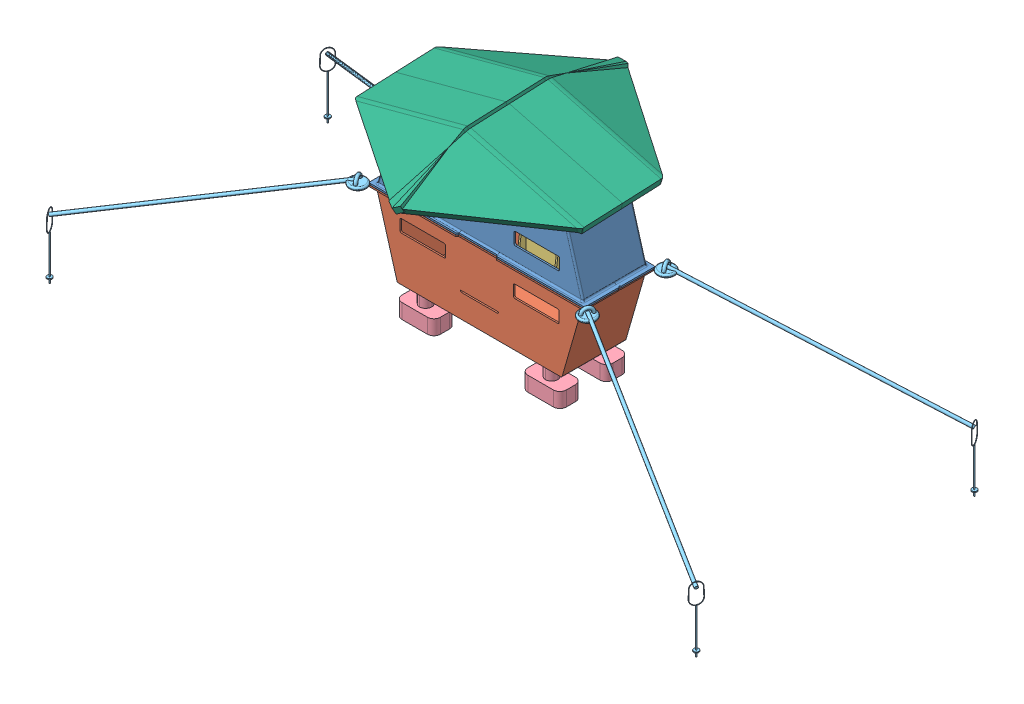
SolidWorks assembly one house, configuration Default. Lengths in mm.
Overall size (1032.67 408.62 463.62).
12 component instances, 6 part files, 7 mates.
Components (placement in the parent):
- cover up-1: cover up [Default] at (-101.023 235.1735 197.7428) size (378.85 222.42 111.15)
- cover down-1: cover down [Default] at (-101.6635 230.0935 197.8948) x (1 0 0.000114) z (-0.000114 0 1) size (338.64 115.9 110.86)
- door-1: door [Default] at (138.6083 344.6201 210.481) x (0 1 0) z (0 0 -1) size (158.5 60.2 14.73)
- rubber pad-1: rubber pad [Default] at (207.2255 205.7771 211.2128) x (-1 0 -0.000114) z (0 1 0) size (60.36 34.67 43.18)
- rubber pad-2: rubber pad [Default] at (9.78 205.7771 211.2128) x (1 0 -0.000114) z (0 1 0) size (60.36 34.67 43.18)
- rubber pad-3: rubber pad [Default] at (207.2255 205.7771 284.223) x (-1 0 0.000114) z (0 1 0) size (60.36 34.67 43.18)
- rubber pad-4: rubber pad [Default] at (9.78 205.7771 284.223) x (1 0 0.000114) z (0 1 0) size (60.36 34.67 43.18)
- anchor-1: anchor [Default] at (615.4516 213.3645 29.7148) x (-0.43106 0 -0.902323) z (0.902323 0 -0.43106) size (26.78 242.75 379.76)
- anchor-2: anchor [Default] at (-398.4461 213.3645 29.7148) x (-0.43106 0 0.902323) z (-0.902323 0 -0.43106) size (26.78 242.75 379.76)
- anchor-3: anchor [Default] at (615.4516 213.3645 465.7211) x (0.43106 0 -0.902323) z (0.902323 0 0.43106) size (26.78 242.75 379.76)
- anchor-4: anchor [Default] at (-398.4461 213.3645 465.7211) x (0.43106 0 0.902323) z (-0.902323 0 0.43106) size (26.78 242.75 379.76)
- wind deflector-1: wind deflector [Default] at (-191.8686 510.2323 82.2371) x (1 0 0) z (0 -0.999048 -0.043619) size (584 406.37 58.81)
Mates (geometry in assembly coordinates):
- Coincident5: coincident anti-aligned: plane of cover up-1 through (-101.023 341.6919 197.7428) normal (0 -1 0); plane of cover down-1 through (-101.6635 341.6919 197.8948) normal (0 1 0)
- Coincident8: coincident anti-aligned: plane of cover up-1 through (78.4103 344.2319 297.7428) normal (1 0 0); plane of door-1 through (78.4103 265.0238 195.749) normal (-1 0 0)
- Coincident11: coincident anti-aligned: plane of cover up-1 through (78.4103 420.9798 297.7428) normal (0 -1 0); plane of door-1 through (80.9503 420.9798 195.749) normal (0 1 0)
- Coincident12: coincident anti-aligned: plane of cover down-1 through (-21.1654 225.7923 297.904) normal (0 -1 0); plane of rubber pad-1 through (207.2255 225.7923 211.2128) normal (0 1 0)
- Coincident14: coincident: line of cover down-1 through (237.4076 227.6293 197.9336) axis (-0.000114 0 1); plane of rubber pad-1 through (237.4061 182.6123 211.2163) normal (1 0 0.000114)
- Coincident23: coincident aligned: plane of cover up-1 through (-101.023 344.2319 197.7428) normal (0 1 0); plane of anchor-1 through (288.4853 344.2319 185.914) normal (0 1 0)
- Tangent4: tangent anti-aligned: cylinder of cover up-1 through (275.2842 341.6919 194.8298) axis (0 1 0) radius 2.54; torus of anchor-1
